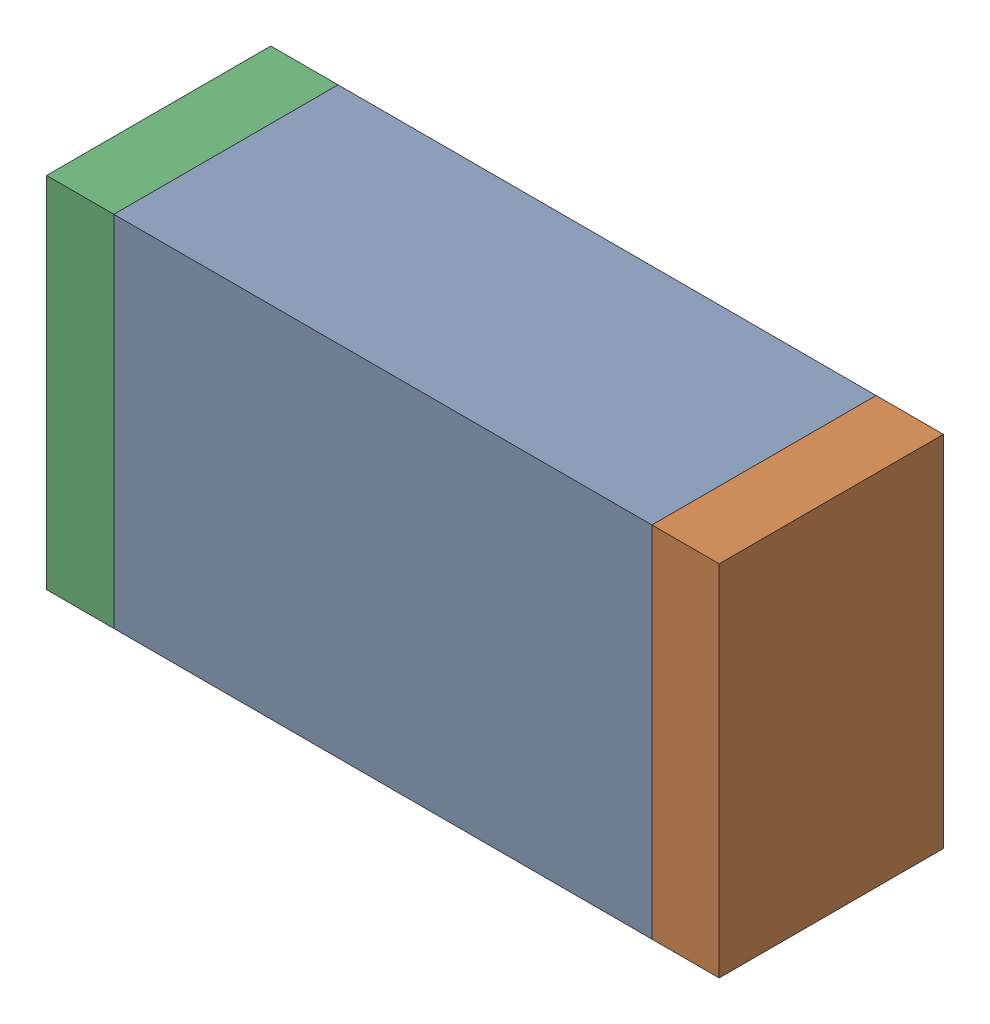
SolidWorks assembly C1, configuration Default. Lengths in mm.
Overall size (1.5 0.8 0.5).
6 component instances, 2 part files, 0 mates.
Components (placement in the parent):
- 836752368-1: 836752368 [Default] at (131.1 5.8 0) size (1.2 0.8 0.5)
  - Extruded-1: Extruded [Default] at origin size (1.2 0.8 0.5)
- 836752496-1: 836752496 [Default] at (131.775 5.8 0) size (0.15 0.8 0.5)
  - Extruded_2-1: Extruded_2 [Default] at origin size (0.15 0.8 0.5)
- 836752496-2: 836752496 [Default] at (130.425 5.8 0) size (0.15 0.8 0.5)
  - Extruded_2-1: Extruded_2 [Default] at origin size (0.15 0.8 0.5)
